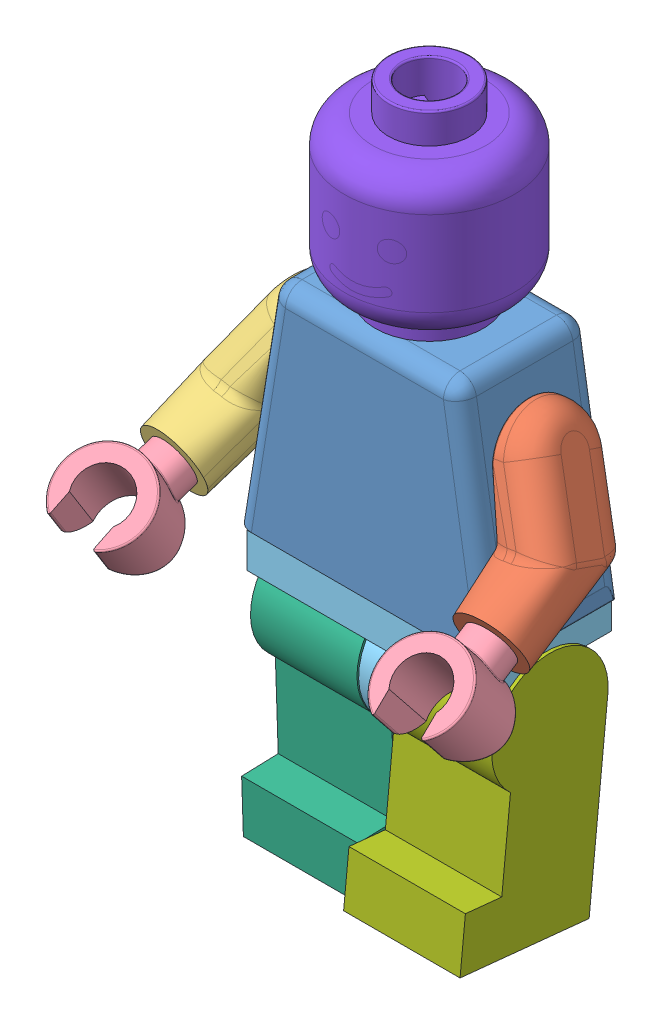
SolidWorks assembly Lego Man, configuration Predeterminado. Lengths in mm.
Overall size (25.44 41.29 18.43).
9 component instances, 8 part files, 20 mates.
Components (placement in the parent):
- Pecho-1: Pecho [Predeterminado] at origin size (15.3 19.2 7.8)
- Brazo 1-2: Brazo 1 [Predeterminado] at (6.669 7.0774 0.5958) x (-0.048692 0.301654 0.952173) z (-0.987221 -0.159355 0) size (7.6 11.61 7.06)
- Brazo 2-2: Brazo 2 [Predeterminado] at (-0.7369 6.1756 0.746) x (0.060963 0.377676 0.923929) z (-0.987221 0.159355 0) size (7.6 11.61 7.06)
- Mano-1: Mano [Predeterminado] at (-9.9077 0.7688 8.1642) x (0.967427 -0.250209 -0.038473) z (-0.114076 -0.566554 0.81609) size (5.19 5.61 11.43)
- Mano-2: Mano [Predeterminado] at (9.4181 0.0712 7.4471) x (0.994926 -0.029138 -0.096299) z (0.055621 -0.638292 0.767782) size (5.19 5.61 11.43)
- Union-1: Union [Predeterminado] at origin size (14.1 13 7.8)
- Pierna Derecha-1: Pierna Derecha [Predeterminado] at (6.75 -4.7 0) x (1 0 0) z (0 -0.033155 0.99945) size (7 14.7 7.8)
- Pierna Izquierda-1: Pierna Izquierda [Predeterminado] at (7.25 -4.7 0) x (1 0 0) z (0 0.100425 0.994945) size (7 14.7 7.8)
- Cabeza-1: Cabeza [Predeterminado] at (0 13.7 0) x (-0.990324 0 0.138776) z (-0.138776 0 -0.990324) size (10.2 11.4 10.2)
Mates (geometry in assembly coordinates):
- Coincidente3: coordinate: point of ?
- Concéntrica3: concentric: cylinder of Pecho-1 through (-8.6968 6.4778 0) axis (0.987221 0.159355 0) radius 1.9; cylinder of Brazo 1-2 through (7.0602 9.0213 0) axis (0.987221 0.159355 0) radius 1.85
- Coincidente4: coincident: plane of Pecho-1 through (5.6 13.7 3.9) normal (0.987221 0.159355 0); plane of Brazo 1-2 through (6.3731 8.9104 0) normal (-0.987221 -0.159355 0)
- Concéntrica4: concentric: cylinder of Pecho-1 through (8.6968 6.4778 0) axis (-0.987221 0.159355 0) radius 1.9; cylinder of Brazo 2-2 through (-7.0602 9.0213 0) axis (-0.987221 0.159355 0) radius 1.85
- Coincidente5: coincident: plane of Pecho-1 through (-7.65 1 3.9) normal (-0.987221 0.159355 0); plane of Brazo 2-2 through (-6.3731 8.9104 0) normal (0.987221 -0.159355 0)
- Coincidente6: coincident: plane of Brazo 2-2 through (-8.9052 5.7745 0.819) normal (-0.061001 -0.377911 0.92383); plane of Mano-1 through (-8.9052 5.7745 0.819) normal (0.061001 0.377911 -0.92383)
- Concéntrica5: concentric: cylinder of Brazo 2-2 through (-8.9052 5.7745 0.819) axis (-0.061001 -0.377911 0.92383) radius 1.125; cylinder of Mano-1 through (-9.6257 1.3108 11.7309) axis (0.061001 0.377911 -0.92383) radius 1.125
- Coincidente7: coincident: plane of Brazo 1-2 through (8.914 5.7199 0.5295) normal (0.072861 -0.451383 0.889351); plane of Mano-2 through (8.914 5.7199 0.5295) normal (-0.072861 0.451383 -0.889351)
- Concéntrica6: concentric: cylinder of Brazo 1-2 through (8.914 5.7199 0.5295) axis (0.072861 -0.451383 0.889351) radius 1.125; cylinder of Mano-2 through (9.7746 0.3883 11.0341) axis (-0.072861 0.451383 -0.889351) radius 1.125
- Coincidente8: coincident: plane of Pecho-1 through (7.65 0 3.9) normal (0 -1 0); plane of Union-1 through (7.05 0 0) normal (0 1 0)
- Ancho1: width: plane of Union-1 through (7.05 0 -3.9) normal (0 0 -1); plane of Union-1 through (7.05 0 3.9) normal (0 0 1); plane of Pecho-1 through (0 0 -3.9) normal (0 0 -1); plane of Pecho-1 through (0 0 3.9) normal (0 0 1)
- Ancho2: width: plane of Union-1 through (-7.05 0 0) normal (-1 0 0); plane of Union-1 through (7.05 0 0) normal (1 0 0); plane of Pecho-1 through (7.65 1 3.9) normal (1 0 0); plane of Pecho-1 through (-7.65 0 3.9) normal (-1 0 0)
- Concéntrica7: concentric: cylinder of Union-1 through (-3.15 -4.7 0) axis (1 0 0) radius 1.2; cylinder of Pierna Derecha-1 through (-7.251 -4.7 0) axis (1 0 0) radius 1.125
- Distancia1: distance = 0.1 mm: plane of Union-1 through (-0.75 0 0) normal (-1 0 0); plane of Pierna Derecha-1 through (-0.85 -4.7 0) normal (1 0 0)
- Concéntrica8: concentric: cylinder of Union-1 through (3.15 -4.7 0) axis (-1 0 0) radius 1.2; cylinder of Pierna Izquierda-1 through (7.251 -4.7 0) axis (-1 0 0) radius 1.125
- Distancia2: distance = 0.1 mm: plane of Pierna Izquierda-1 through (0.85 -4.7 0) normal (-1 0 0); plane of Union-1 through (0.75 0 0) normal (1 0 0)
- Ángulo límite1: limit planar angle = 0.033161 rad: line of Pierna Derecha-1 through (-7.25 -4.584 -3.4981) axis (0 -0.99945 -0.033155); line of Union-1 through (-7.05 0 3.9) axis (0 -1 0)
- Ángulo límite2: limit planar angle = 0.100595 rad: line of Union-1 through (7.05 0 3.9) axis (0 -1 0); line of Pierna Izquierda-1 through (7.25 -5.0515 -3.4823) axis (0 -0.994945 0.100425)
- Coincidente15: coincident: plane of Pecho-1 through (-5.6 13.7 3.9) normal (0 1 0); plane of Cabeza-1 through (0.34 13.7 2.4263) normal (0 -1 0)
- Concéntrica9: concentric: cylinder of Pecho-1 through (0 19.2 0) axis (0 -1 0) radius 2.4; cylinder of Cabeza-1 through (0 13.7 0) axis (0 -1 0) radius 2.45
